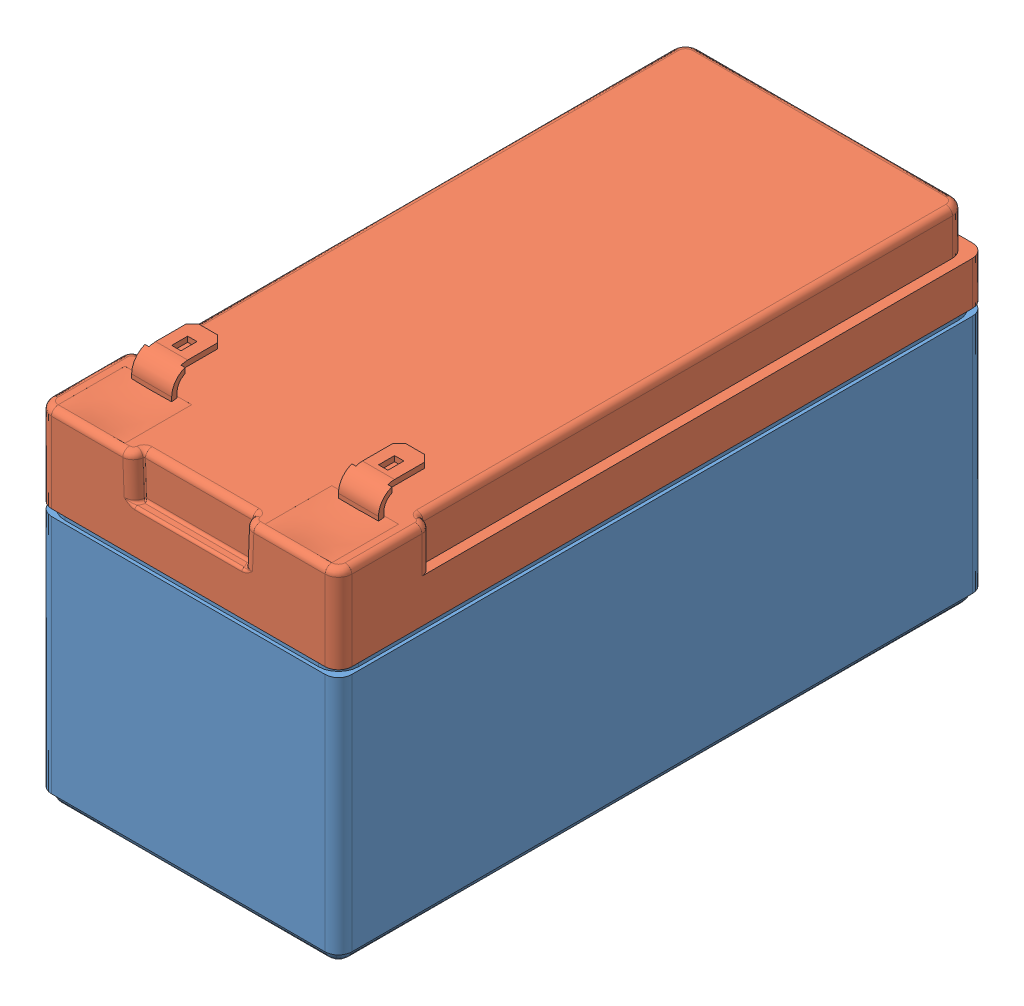
SolidWorks assembly KT-1213, 12 V, 1.3 Ah, AGM Lead-Acid Battery, configuration Default. Lengths in mm.
Overall size (45 55.5 97.4).
2 component instances, 2 part files, 4 mates.
Components (placement in the parent):
- Main Body, KT-1213, 12 V, 1.3 Ah, AGM Lead-Acid Battery-1: Main Body, KT-1213, 12 V, 1.3 Ah, AGM Lead-Acid Battery [Default] at origin size (45 44 97)
- Cover, KT-1213, 12 V, 1.3 Ah, AGM Lead-Acid Battery-1: Cover, KT-1213, 12 V, 1.3 Ah, AGM Lead-Acid Battery [Default] at (0 20 0) size (45 16.5 97.4)
Mates (geometry in assembly coordinates):
- Coincident1: coordinate: point of Main Body, KT-1213, 12 V, 1.3 Ah, AGM Lead-Acid Battery-1
- Coincident2: coincident aligned: plane of Cover, KT-1213, 12 V, 1.3 Ah, AGM Lead-Acid Battery-1 through (0 20 0) normal (1 0 0)
- Coincident3: coincident aligned: plane of Cover, KT-1213, 12 V, 1.3 Ah, AGM Lead-Acid Battery-1 through (0 20 0) normal (0 0 1)
- Distance1: distance = 1 mm anti-aligned: plane of Main Body, KT-1213, 12 V, 1.3 Ah, AGM Lead-Acid Battery-1 through (0 19 0) normal (0 1 0); plane of Cover, KT-1213, 12 V, 1.3 Ah, AGM Lead-Acid Battery-1 through (0 20 0) normal (0 -1 0)
